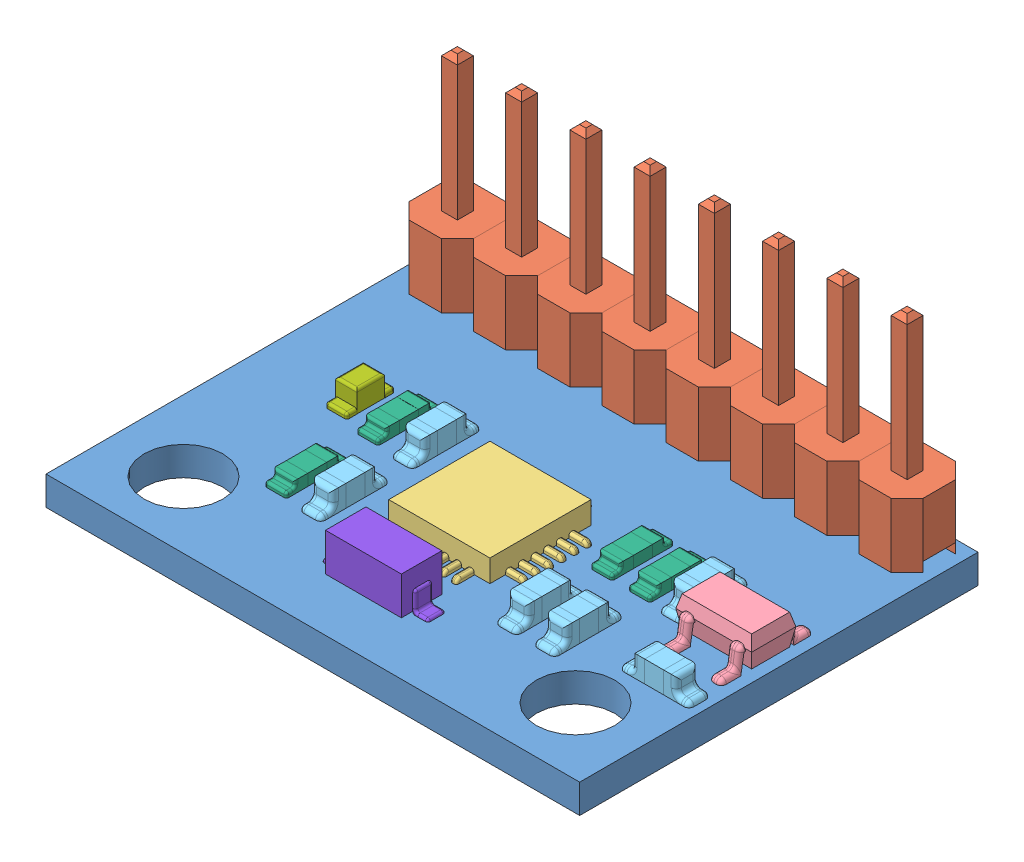
SolidWorks assembly MPU 6050 IMU, configuration Default. Lengths in mm.
Overall size (21.1 10.56 15.88).
23 component instances, 8 part files, 33 mates.
Components (placement in the parent):
- Base-1: Base [Default] at (7.2489 10.9584 16.5726) size (21.1 1.14 15.75)
- pin header-1: pin header [Default] at (16.1389 11.5299 9.8416) x (-1 0 0) z (0 0 -1) size (2.54 10.56 2.54)
- pin header-2: pin header [Default] at (13.5989 11.5299 9.8416) x (-1 0 0) z (0 0 -1) size (2.54 10.56 2.54)
- pin header-3: pin header [Default] at (11.0589 11.5299 9.8416) x (-1 0 0) z (0 0 -1) size (2.54 10.56 2.54)
- pin header-4: pin header [Default] at (8.5189 11.5299 9.8416) x (-1 0 0) z (0 0 -1) size (2.54 10.56 2.54)
- pin header-5: pin header [Default] at (5.9789 11.5299 9.8416) x (-1 0 0) z (0 0 -1) size (2.54 10.56 2.54)
- pin header-6: pin header [Default] at (3.4389 11.5299 9.8416) x (-1 0 0) z (0 0 -1) size (2.54 10.56 2.54)
- pin header-7: pin header [Default] at (0.8989 11.5299 9.8416) x (-1 0 0) z (0 0 -1) size (2.54 10.56 2.54)
- pin header-8: pin header [Default] at (-1.6411 11.5299 9.8416) x (-1 0 0) z (0 0 -1) size (2.54 10.56 2.54)
- sensor chip-1: sensor chip [Default] at (7.2489 11.5499 17.4466) size (5.4 0.9 5.4)
- S2NH chip-1: S2NH chip [Default] at (16.0989 12.3799 16.5726) size (3 1.35 3.65)
- Resistor small-3: Resistor small [Default] at (16.0989 11.5314 19.3726) size (2.75 0.99 1)
- Resistor small-4: Resistor small [Default] at (13.9739 11.5314 15.6976) x (0 0 -1) z (1 0 0) size (2.75 0.99 1)
- Resistor small black-3: Resistor small black [Default] at (12.6239 11.5299 15.6976) x (0 0 1) z (-1 0 0) size (2.45 0.6 1.02)
- Resistor small black-4: Resistor small black [Default] at (11.1239 11.5299 15.6976) x (0 0 1) z (-1 0 0) size (2.45 0.6 1.02)
- Resistor small-5: Resistor small [Default] at (12.6239 11.5314 19.3216) x (0 0 -1) z (1 0 0) size (2.75 0.99 1)
- Resistor small-6: Resistor small [Default] at (11.1239 11.5314 19.3216) x (0 0 -1) z (1 0 0) size (2.75 0.99 1)
- Resistor small-7: Resistor small [Default] at (3.3739 11.5314 19.3216) x (0 0 -1) z (1 0 0) size (2.75 0.99 1)
- Resistor small black-5: Resistor small black [Default] at (1.8739 11.5299 15.6972) x (0 0 -1) z (1 0 0) size (2.45 0.6 1.02)
- Resistor small-8: Resistor small [Default] at (3.3739 11.5314 15.6976) x (0 0 1) z (-1 0 0) size (2.75 0.99 1)
- Small LED-1: Small LED [Default] at (0.3689 11.5299 15.6976) size (0.85 0.84 1.9)
- Resistor small black-6: Resistor small black [Default] at (1.8739 11.5299 19.3216) x (0 0 1) z (-1 0 0) size (2.45 0.6 1.02)
- Resistor black-1: Resistor black [Default] at (7.2489 12.3799 21.6466) size (4.2 1.6 1.6)
Mates (geometry in assembly coordinates):
- Concentric1: concentric: cylinder of Base-1 through (16.1389 11.5299 9.8416) axis (0 -1 0) radius 0.508; point of pin header-1
- Coincident4: coincident anti-aligned: plane of Base-1 through (7.2489 11.5299 16.5726) normal (0 1 0); plane of pin header-1 through (16.1389 11.5299 9.8416) normal (0 -1 0)
- Parallel1: parallel aligned: plane of Base-1 through (17.7989 11.5299 24.4466) normal (1 0 0); plane of pin header-1 through (17.4089 14.0699 9.2066) normal (1 0 0)
- Coincident6: coincident anti-aligned: plane of Base-1 through (7.2489 11.5299 16.5726) normal (0 1 0); plane of sensor chip-1 through (7.2489 11.5299 17.4466) normal (0 -1 0)
- Coincident7: coincident aligned: plane of Base-1 through (7.2489 10.9584 16.5726) normal (1 0 0); plane of sensor chip-1 through (7.2489 11.5499 17.4466) normal (1 0 0)
- Distance1: distance = 5 mm aligned: plane of sensor chip-1 through (5.2489 12.4299 19.4466) normal (0 0 1); plane of Base-1 through (-3.3011 11.5299 24.4466) normal (0 0 1)
- Coincident8: coincident anti-aligned: plane of Base-1 through (7.2489 11.5299 16.5726) normal (0 1 0); plane of S2NH chip-1 through (16.0989 11.5299 16.5726) normal (0 -1 0)
- Coincident9: coincident aligned: plane of Base-1 through (7.2489 10.9584 16.5726) normal (0 0 1); plane of S2NH chip-1 through (16.0989 12.3799 16.5726) normal (0 0 1)
- Distance2: distance = 0.2 mm: line of S2NH chip-1 through (17.5989 12.3799 17.4476) axis (0 0 -1); plane of Base-1 through (17.7989 11.5299 24.4466) normal (1 0 0)
- Coincident19: coincident anti-aligned: plane of Base-1 through (7.2489 11.5299 16.5726) normal (0 1 0); plane of Resistor small-3 through (16.9739 11.5299 19.8026) normal (0 -1 0)
- Coincident20: coincident aligned: plane of S2NH chip-1 through (16.0989 12.3799 16.5726) normal (1 0 0); plane of Resistor small-3 through (16.0989 11.5314 19.3726) normal (1 0 0)
- Distance5: distance = 1.5 mm: line of S2NH chip-1 through (15.3221 12.3799 17.4476) axis (1 0 0); plane of Resistor small-3 through (16.4739 11.5314 18.9476) normal (0 0 -1)
- Coincident22: coincident anti-aligned: plane of Base-1 through (7.2489 11.5299 16.5726) normal (0 1 0); plane of Resistor small-4 through (14.4039 11.5299 14.8226) normal (0 -1 0)
- Coincident24: coincident: line of S2NH chip-1 through (16.8757 12.3799 15.6976) axis (-1 0 0); plane of Resistor small-4 through (13.9739 11.5314 15.6976) normal (0 0 -1)
- Distance6: distance = 0.2 mm: plane of Resistor small-4 through (14.3989 11.5314 15.3226) normal (1 0 0); line of S2NH chip-1 through (14.5989 12.3799 15.6976) axis (0 0 1)
- Coincident26: coincident anti-aligned: plane of Base-1 through (7.2489 11.5299 16.5726) normal (0 1 0); plane of Resistor small black-3 through (12.1989 11.5299 16.0726) normal (0 -1 0)
- Coincident28: coincident anti-aligned: plane of Resistor small-4 through (13.9739 11.5314 15.6976) normal (0 0 -1); plane of Resistor small black-3 through (12.6239 11.5299 15.6976) normal (0 0 1)
- Distance7: distance = 0.5 mm anti-aligned: plane of Resistor small-4 through (13.5489 11.5314 15.3226) normal (-1 0 0); plane of Resistor small black-3 through (13.0489 11.5299 16.0726) normal (1 0 0)
- Coincident30: coincident anti-aligned: plane of Base-1 through (7.2489 11.5299 16.5726) normal (0 1 0); plane of Resistor small-5 through (13.0539 11.5299 18.4466) normal (0 -1 0)
- Coincident31: coincident anti-aligned: plane of Resistor small black-3 through (12.6239 11.5299 15.6976) normal (-1 0 0); plane of Resistor small-5 through (12.6239 11.5314 19.3216) normal (1 0 0)
- Distance8: distance = 4.25 mm aligned: plane of Resistor small-5 through (12.6239 11.5314 20.1966) normal (0 0 1); plane of Base-1 through (-3.3011 11.5299 24.4466) normal (0 0 1)
- Coincident33: coincident anti-aligned: plane of Base-1 through (7.2489 11.5299 16.5726) normal (0 1 0); plane of Resistor small-8 through (2.9439 11.5299 14.8226) normal (0 -1 0)
- Coincident34: coincident anti-aligned: plane of Resistor small-7 through (3.3739 11.5314 19.3216) normal (1 0 0); plane of Resistor small-8 through (3.3739 11.5314 15.6976) normal (-1 0 0)
- Coincident36: coincident: line of S2NH chip-1 through (15.8757 12.3799 15.6976) axis (-1 0 0); plane of Resistor small-8 through (3.3739 11.5314 15.6976) normal (0 0 1)
- Coincident37: coincident anti-aligned: plane of Base-1 through (7.2489 11.5299 16.5726) normal (0 1 0); plane of Small LED-1 through (0.3689 11.5299 15.6976) normal (0 -1 0)
- Coincident38: coincident: line of S2NH chip-1 through (15.8757 12.3799 15.6976) axis (-1 0 0); plane of Small LED-1 through (0.3689 11.5299 15.6976) normal (0 0 1)
- Distance9: distance = 1.5 mm aligned: plane of Small LED-1 through (-0.0511 12.3699 16.2476) normal (-1 0 0); plane of Resistor small black-5 through (1.4489 11.5299 15.3222) normal (-1 0 0)
- Coincident40: coincident anti-aligned: plane of Base-1 through (7.2489 11.5299 16.5726) normal (0 1 0); plane of Resistor small black-6 through (1.4489 11.5299 19.6966) normal (0 -1 0)
- Coincident41: coincident anti-aligned: plane of Resistor small black-5 through (1.8739 11.5299 15.6972) normal (1 0 0); plane of Resistor small black-6 through (1.8739 11.5299 19.3216) normal (-1 0 0)
- Coincident42: coincident anti-aligned: plane of Resistor small-7 through (3.3739 11.5314 19.3216) normal (0 0 -1); plane of Resistor small black-6 through (1.8739 11.5299 19.3216) normal (0 0 1)
- Coincident43: coincident anti-aligned: plane of Base-1 through (7.2489 11.5299 16.5726) normal (0 1 0); plane of Resistor black-1 through (5.6489 11.5299 21.9966) normal (0 -1 0)
- Coincident44: coincident aligned: plane of Base-1 through (7.2489 10.9584 16.5726) normal (1 0 0); plane of Resistor black-1 through (7.2489 12.3799 21.6466) normal (1 0 0)
- Distance10: distance = 2 mm aligned: plane of Resistor black-1 through (5.7489 13.1299 22.4466) normal (0 0 1); plane of Base-1 through (-3.3011 11.5299 24.4466) normal (0 0 1)
